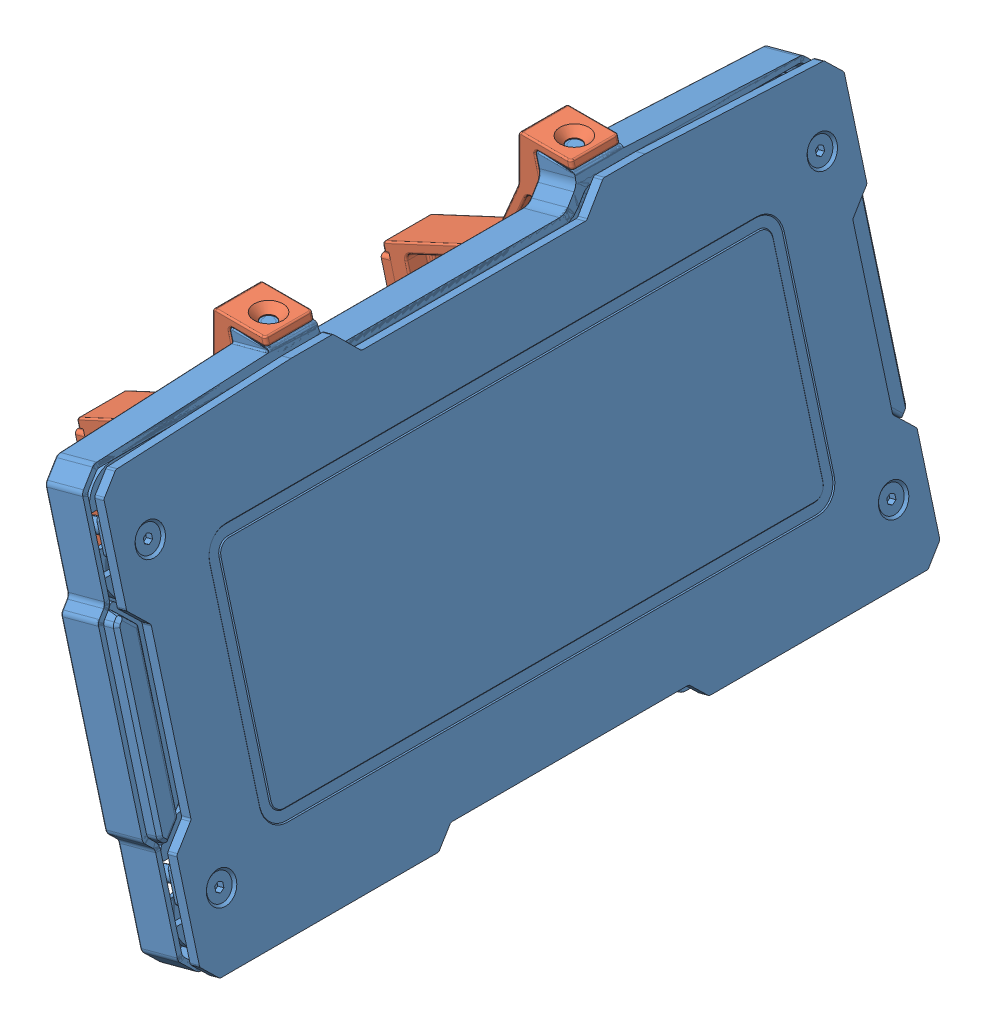
SolidWorks assembly 大装甲(带支架), configuration 默认. Lengths in mm.
Overall size (110.83 141.2 236.09).
3 component instances, 2 part files, 6 mates.
Components (placement in the parent):
- 大装甲-1: 大装甲 [默认] at (-134.1308 -11.5841 236.1185) size (53.57 127.71 236.09)
- 装甲支撑架（B）-1: 装甲支撑架（B） [默认] at (-81.0438 -38.8658 188.6185) x (0 0 1) z (-0.965926 -0.258819 0) size (15.02 127.12 71.15)
- 装甲支撑架（B）-2: 装甲支撑架（B） [默认] at (-81.0438 -38.8658 283.6185) x (0 0 1) z (-0.965926 -0.258819 0) size (15.02 127.12 71.15)
Mates (geometry in assembly coordinates):
- 重合1: coincident: plane of 大装甲-1 through (-31.8391 -3.6459 236.1185) normal (-0.965926 -0.258819 0); plane of 装甲支撑架（B）-1 through (-49.624 62.728 180.75) normal (0.965926 0.258819 0)
- 重合2: coincident: plane of 大装甲-1 through (-49.624 62.728 196.1185) normal (0 1 0); plane of 装甲支撑架（B）-1 through (-37.7183 62.728 213.4351) normal (0 -1 0)
- 重合3: coincident aligned: plane of 大装甲-1 through (-31.8391 -3.6459 196.1185) normal (0 0 1); plane of 装甲支撑架（B）-1 through (-26.3303 -24.2053 196.1185) normal (0 0 1)
- 重合4: coincident: plane of 大装甲-1 through (-31.8391 -3.6459 236.1185) normal (-0.965926 -0.258819 0); plane of 装甲支撑架（B）-2 through (-49.624 62.728 276.1185) normal (0.965926 0.258819 0)
- 重合5: coincident: plane of 大装甲-1 through (-31.8391 -3.6459 276.1185) normal (0 0 -1); plane of 装甲支撑架（B）-2 through (-26.3303 -24.2053 276.1185) normal (0 0 -1)
- 重合6: coincident anti-aligned: plane of 大装甲-1 through (-49.624 62.728 276.1185) normal (0 1 0); plane of 装甲支撑架（B）-2 through (-37.7183 62.728 308.8037) normal (0 -1 0)
